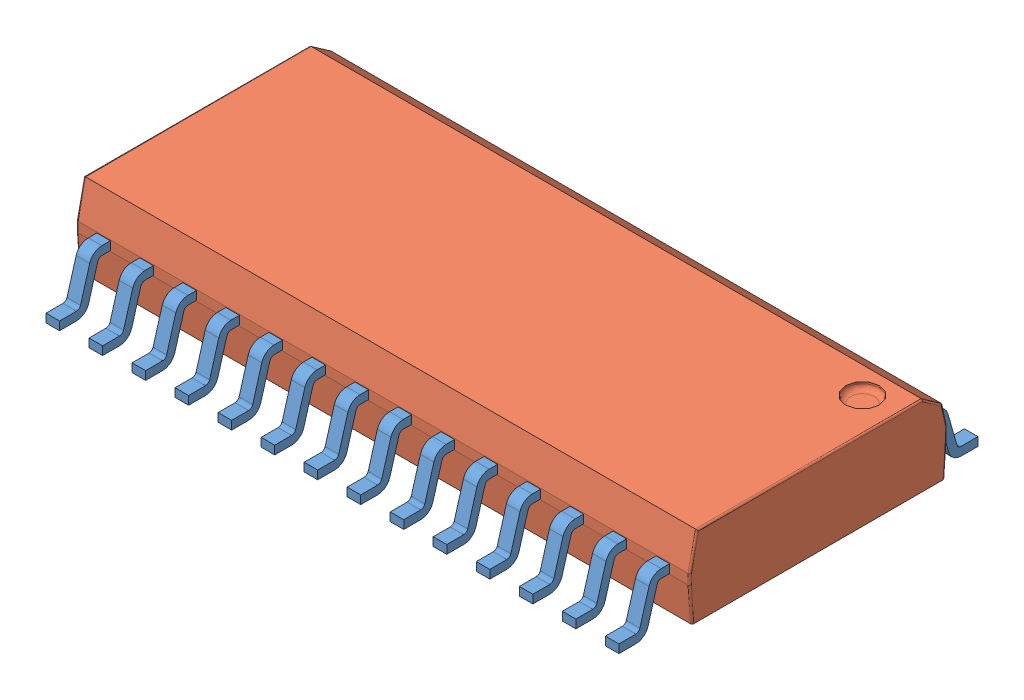
SolidWorks assembly User Library-SOIC-28-300, configuration Default. Lengths in mm.
Overall size (18.1 2.6 10.6).
29 component instances, 2 part files, 0 mates.
Components (placement in the parent):
- User Library-SOIC-28-300_pin_SOIC_SO-300_1-1: User Library-SOIC-28-300_pin_SOIC_SO-300_1 [Default] at (8.26 0 3.8) size (0.4 1.55 1.5)
- User Library-SOIC-28-300_pin_SOIC_SO-300_1-2: User Library-SOIC-28-300_pin_SOIC_SO-300_1 [Default] at (3.18 0 -3.8) x (-1 0 0) z (0 0 -1) size (0.4 1.55 1.5)
- User Library-SOIC-28-300_pin_SOIC_SO-300_1-3: User Library-SOIC-28-300_pin_SOIC_SO-300_1 [Default] at (6.99 0 -3.8) x (-1 0 0) z (0 0 -1) size (0.4 1.55 1.5)
- User Library-SOIC-28-300_pin_SOIC_SO-300_1-4: User Library-SOIC-28-300_pin_SOIC_SO-300_1 [Default] at (-1.9 0 -3.8) x (-1 0 0) z (0 0 -1) size (0.4 1.55 1.5)
- User Library-SOIC-28-300_pin_SOIC_SO-300_1-5: User Library-SOIC-28-300_pin_SOIC_SO-300_1 [Default] at (5.72 0 3.8) size (0.4 1.55 1.5)
- User Library-SOIC-28-300_pin_SOIC_SO-300_1-6: User Library-SOIC-28-300_pin_SOIC_SO-300_1 [Default] at (-1.9 0 3.8) size (0.4 1.55 1.5)
- User Library-SOIC-28-300_pin_SOIC_SO-300_1-7: User Library-SOIC-28-300_pin_SOIC_SO-300_1 [Default] at (-4.44 0 -3.8) x (-1 0 0) z (0 0 -1) size (0.4 1.55 1.5)
- User Library-SOIC-28-300_SOIC_300_SOIC_18.1X7.6_1-1: User Library-SOIC-28-300_SOIC_300_SOIC_18.1X7.6_1 [Default] at origin size (18.1 2.35 7.6)
- User Library-SOIC-28-300_pin_SOIC_SO-300_1-8: User Library-SOIC-28-300_pin_SOIC_SO-300_1 [Default] at (1.91 0 -3.8) x (-1 0 0) z (0 0 -1) size (0.4 1.55 1.5)
- User Library-SOIC-28-300_pin_SOIC_SO-300_1-9: User Library-SOIC-28-300_pin_SOIC_SO-300_1 [Default] at (-8.25 0 -3.8) x (-1 0 0) z (0 0 -1) size (0.4 1.55 1.5)
- User Library-SOIC-28-300_pin_SOIC_SO-300_1-10: User Library-SOIC-28-300_pin_SOIC_SO-300_1 [Default] at (8.26 0 -3.8) x (-1 0 0) z (0 0 -1) size (0.4 1.55 1.5)
- User Library-SOIC-28-300_pin_SOIC_SO-300_1-11: User Library-SOIC-28-300_pin_SOIC_SO-300_1 [Default] at (0.64 0 3.8) size (0.4 1.55 1.5)
- User Library-SOIC-28-300_pin_SOIC_SO-300_1-12: User Library-SOIC-28-300_pin_SOIC_SO-300_1 [Default] at (4.45 0 3.8) size (0.4 1.55 1.5)
- User Library-SOIC-28-300_pin_SOIC_SO-300_1-13: User Library-SOIC-28-300_pin_SOIC_SO-300_1 [Default] at (-5.71 0 -3.8) x (-1 0 0) z (0 0 -1) size (0.4 1.55 1.5)
- User Library-SOIC-28-300_pin_SOIC_SO-300_1-14: User Library-SOIC-28-300_pin_SOIC_SO-300_1 [Default] at (-4.44 0 3.8) size (0.4 1.55 1.5)
- User Library-SOIC-28-300_pin_SOIC_SO-300_1-15: User Library-SOIC-28-300_pin_SOIC_SO-300_1 [Default] at (3.18 0 3.8) size (0.4 1.55 1.5)
- User Library-SOIC-28-300_pin_SOIC_SO-300_1-16: User Library-SOIC-28-300_pin_SOIC_SO-300_1 [Default] at (-0.63 0 -3.8) x (-1 0 0) z (0 0 -1) size (0.4 1.55 1.5)
- User Library-SOIC-28-300_pin_SOIC_SO-300_1-17: User Library-SOIC-28-300_pin_SOIC_SO-300_1 [Default] at (-6.98 0 3.8) size (0.4 1.55 1.5)
- User Library-SOIC-28-300_pin_SOIC_SO-300_1-18: User Library-SOIC-28-300_pin_SOIC_SO-300_1 [Default] at (-8.25 0 3.8) size (0.4 1.55 1.5)
- User Library-SOIC-28-300_pin_SOIC_SO-300_1-19: User Library-SOIC-28-300_pin_SOIC_SO-300_1 [Default] at (6.99 0 3.8) size (0.4 1.55 1.5)
- User Library-SOIC-28-300_pin_SOIC_SO-300_1-20: User Library-SOIC-28-300_pin_SOIC_SO-300_1 [Default] at (-6.98 0 -3.8) x (-1 0 0) z (0 0 -1) size (0.4 1.55 1.5)
- User Library-SOIC-28-300_pin_SOIC_SO-300_1-21: User Library-SOIC-28-300_pin_SOIC_SO-300_1 [Default] at (4.45 0 -3.8) x (-1 0 0) z (0 0 -1) size (0.4 1.55 1.5)
- User Library-SOIC-28-300_pin_SOIC_SO-300_1-22: User Library-SOIC-28-300_pin_SOIC_SO-300_1 [Default] at (0.64 0 -3.8) x (-1 0 0) z (0 0 -1) size (0.4 1.55 1.5)
- User Library-SOIC-28-300_pin_SOIC_SO-300_1-23: User Library-SOIC-28-300_pin_SOIC_SO-300_1 [Default] at (-3.17 0 3.8) size (0.4 1.55 1.5)
- User Library-SOIC-28-300_pin_SOIC_SO-300_1-24: User Library-SOIC-28-300_pin_SOIC_SO-300_1 [Default] at (1.91 0 3.8) size (0.4 1.55 1.5)
- User Library-SOIC-28-300_pin_SOIC_SO-300_1-25: User Library-SOIC-28-300_pin_SOIC_SO-300_1 [Default] at (-3.17 0 -3.8) x (-1 0 0) z (0 0 -1) size (0.4 1.55 1.5)
- User Library-SOIC-28-300_pin_SOIC_SO-300_1-26: User Library-SOIC-28-300_pin_SOIC_SO-300_1 [Default] at (-0.63 0 3.8) size (0.4 1.55 1.5)
- User Library-SOIC-28-300_pin_SOIC_SO-300_1-27: User Library-SOIC-28-300_pin_SOIC_SO-300_1 [Default] at (-5.71 0 3.8) size (0.4 1.55 1.5)
- User Library-SOIC-28-300_pin_SOIC_SO-300_1-28: User Library-SOIC-28-300_pin_SOIC_SO-300_1 [Default] at (5.72 0 -3.8) x (-1 0 0) z (0 0 -1) size (0.4 1.55 1.5)
